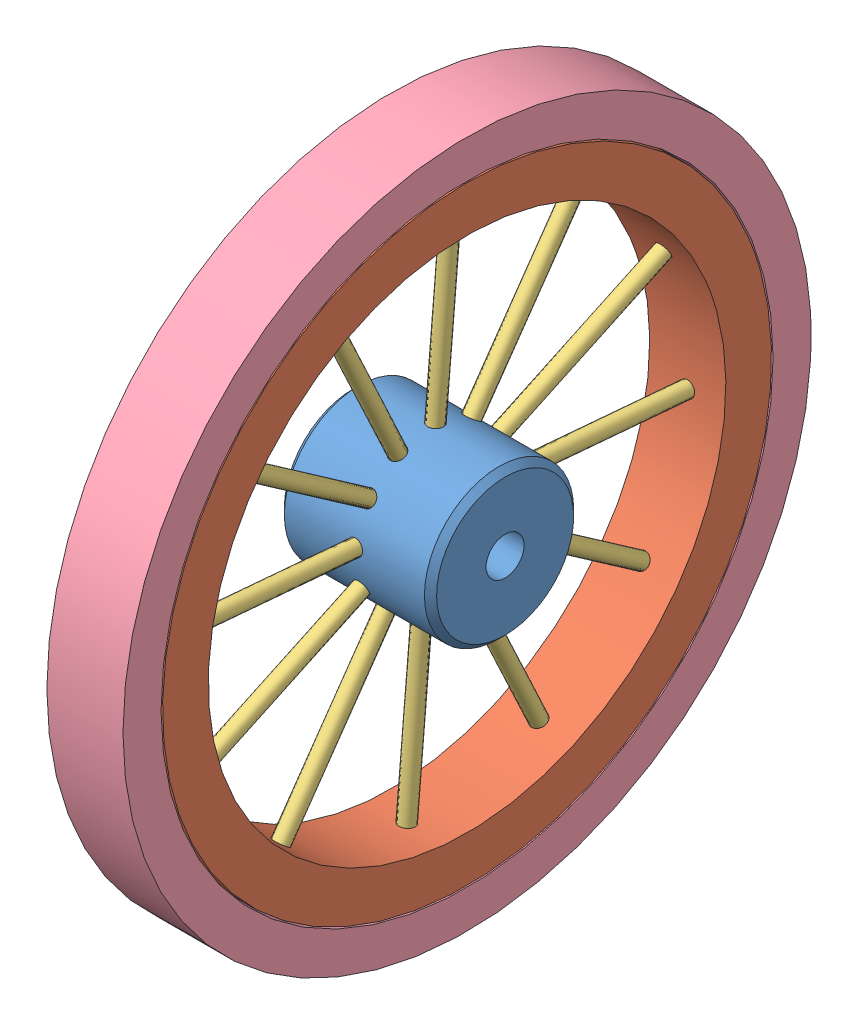
SolidWorks assembly Wheel, configuration Default. Lengths in mm.
Overall size (25.4 129.14 129.14).
15 component instances, 4 part files, 30 mates.
Components (placement in the parent):
- Hub-1: Hub [Default] at (11.6263 10.9898 19.9037) size (25.4 24.89 24.89)
- InnerRim-1: InnerRim [Default] at (11.6263 10.9898 19.9037) x (1 0 0) z (0 -0.325508 0.945539) size (12.7 101.6 101.6)
- Spoke-1: Spoke [Default] at (11.6263 -16.3912 7.1017) x (0.733186 -0.288022 0.616021) z (-0.680028 -0.310536 0.664175) size (2.54 40.64 2.54)
- Spoke-2: Spoke [Default] at (11.6263 -19.1238 22.5073) x (0.45302 0.076792 0.888187) z (-0.8915 0.039022 0.451337) size (2.54 40.64 2.54)
- Spoke-3: Spoke [Default] at (11.6263 -6.3218 -4.8737) x (-0.558086 -0.680204 0.47525) z (-0.829783 0.457484 -0.319638) size (2.54 40.64 2.54)
- Spoke-4: Spoke [Default] at (11.6263 -13.7876 37.2153) x (1 0 0) z (0 0.572739 0.819737) size (2.54 40.64 2.54)
- Spoke-5: Spoke [Default] at (11.6263 -1.8122 47.2847) x (0.999266 -0.0347 -0.016224) z (0.038306 0.905211 0.423233) size (2.54 40.64 2.54)
- Spoke-6: Spoke [Default] at (11.6263 8.3862 -10.21) x (0.430926 -0.899033 0.07773) z (-0.902387 -0.429324 0.037119) size (2.54 40.64 2.54)
- Spoke-7: Spoke [Default] at (11.6263 23.7918 -7.4773) x (1 0 0) z (0 0.905876 0.423544) size (2.54 40.64 2.54)
- Spoke-8: Spoke [Default] at (11.6263 13.5934 50.0173) x (0.808821 -0.58587 0.050654) z (-0.588055 -0.805815 0.06967) size (2.54 40.64 2.54)
- Spoke-9: Spoke [Default] at (11.6263 28.3014 44.6811) x (0.274974 0.788138 -0.550661) z (0.961452 -0.225406 0.157488) size (2.54 40.64 2.54)
- Spoke-10: Spoke [Default] at (11.6263 41.1035 17.3001) x (0.021573 0.086118 0.996051) z (-0.999767 0.001858 0.021493) size (2.54 40.64 2.54)
- Spoke-11: Spoke [Default] at (11.6263 35.7672 2.5921) x (0.597522 0.459253 0.657309) z (-0.801853 0.342224 0.489811) size (2.54 40.64 2.54)
- Spoke-12: Spoke [Default] at (11.6263 38.3708 32.7057) x (0.995605 -0.039667 0.08484) z (-0.093656 -0.421682 0.901894) size (2.54 40.64 2.54)
- OuterRim-1: OuterRim [Default] at (11.6263 10.9898 19.9037) size (12.7 114.81 114.81)
Mates (geometry in assembly coordinates):
- Coincident4: coincident aligned: plane of Hub-1 through (11.6263 10.9898 19.9037) normal (1 0 0); plane of InnerRim-1
- Concentric1: concentric aligned: cylinder of Hub-1 through (24.3263 10.9898 19.9037) axis (-1 0 0) radius 12.446; cylinder of InnerRim-1 through (17.9763 10.9898 19.9037) axis (-1 0 0) radius 43.18
- Concentric2: concentric anti-aligned: cylinder of Hub-1 through (11.6263 22.2643 25.1751) axis (0 0.905876 0.423544) radius 1.2891; cylinder of Spoke-12 through (11.6263 56.7782 41.3121) axis (0 -0.905876 -0.423544) radius 1.27
- Concentric3: concentric anti-aligned: cylinder of InnerRim-1 through (11.6263 57.0083 41.4197) axis (0 0.905876 0.423544) radius 1.2891; cylinder of Spoke-12 through (11.6263 56.7782 41.3121) axis (0 -0.905876 -0.423544) radius 1.27
- Coincident5: coincident anti-aligned: circle of Hub-1; plane of Spoke-12 through (11.6263 19.9634 24.0993) normal (0 -0.905876 -0.423544)
- Concentric4: concentric anti-aligned: cylinder of InnerRim-1 through (11.6263 61.601 15.5279) axis (0 0.996283 -0.086138) radius 1.2891; cylinder of Spoke-10 through (11.6263 61.3479 15.5497) axis (0 -0.996283 0.086138) radius 1.27
- Concentric5: concentric anti-aligned: cylinder of Hub-1 through (11.6263 23.3895 18.8316) axis (0 0.996283 -0.086138) radius 1.2891; cylinder of Spoke-10 through (11.6263 61.3479 15.5497) axis (0 -0.996283 0.086138) radius 1.27
- Concentric6: concentric anti-aligned: cylinder of InnerRim-1 through (11.6263 52.6325 -9.1915) axis (0 0.819737 -0.572739) radius 1.2891; cylinder of Spoke-11 through (11.6263 52.4243 -9.046) axis (0 -0.819737 0.572739) radius 1.27
- Concentric7: concentric anti-aligned: cylinder of InnerRim-1 through (11.6263 32.5058 -26.1148) axis (0 0.423544 -0.905876) radius 1.2891; cylinder of Spoke-7 through (11.6263 32.3982 -25.8847) axis (0 -0.423544 0.905876) radius 1.27
- Concentric8: concentric aligned: cylinder of InnerRim-1 through (11.6263 6.614 -30.7075) axis (0 -0.086138 -0.996283) radius 1.2891; cylinder of Spoke-6 through (11.6263 10.1365 10.0345) axis (0 -0.086138 -0.996283) radius 1.27
- Concentric9: concentric aligned: cylinder of InnerRim-1 through (11.6263 -18.1054 -21.739) axis (0 -0.572739 -0.819737) radius 1.2891; cylinder of Spoke-3 through (11.6263 5.3162 11.7834) axis (0 -0.572739 -0.819737) radius 1.27
- Concentric10: concentric aligned: cylinder of InnerRim-1 through (11.6263 -35.0287 -1.6123) axis (0 -0.905876 -0.423544) radius 1.2891; cylinder of Spoke-1 through (11.6263 2.0162 15.7081) axis (0 -0.905876 -0.423544) radius 1.27
- Concentric11: concentric aligned: cylinder of InnerRim-1 through (11.6263 -39.6214 24.2795) axis (0 -0.996283 0.086138) radius 1.2891; cylinder of Spoke-2 through (11.6263 1.1206 20.757) axis (0 -0.996283 0.086138) radius 1.27
- Concentric12: concentric aligned: cylinder of InnerRim-1 through (11.6263 -30.6529 48.9989) axis (0 -0.819737 0.572739) radius 1.2891; cylinder of Spoke-4 through (11.6263 2.8695 25.5772) axis (0 -0.819737 0.572739) radius 1.27
- Concentric13: concentric aligned: cylinder of InnerRim-1 through (11.6263 -10.5262 65.9222) axis (0 -0.423544 0.905876) radius 1.2891; cylinder of Spoke-5 through (11.6263 6.7942 28.8773) axis (0 -0.423544 0.905876) radius 1.27
- Concentric14: concentric anti-aligned: cylinder of InnerRim-1 through (11.6263 15.3656 70.5149) axis (0 0.086138 0.996283) radius 1.2891; cylinder of Spoke-8 through (11.6263 15.3437 70.2618) axis (0 -0.086138 -0.996283) radius 1.27
- Concentric15: concentric anti-aligned: cylinder of InnerRim-1 through (11.6263 40.085 61.5464) axis (0 0.572739 0.819737) radius 1.2891; cylinder of Spoke-9 through (11.6263 39.9395 61.3381) axis (0 -0.572739 -0.819737) radius 1.27
- Coincident6: coincident anti-aligned: circle of Hub-1; plane of Spoke-9 through (11.6263 16.6634 28.024) normal (0 -0.572739 -0.819737)
- Coincident7: coincident anti-aligned: circle of Hub-1; plane of Spoke-8 through (11.6263 11.8431 29.7729) normal (0 -0.086138 -0.996283)
- Coincident8: coincident anti-aligned: circle of Hub-1; plane of Spoke-5 through (11.6263 6.7942 28.8773) normal (0 0.423544 -0.905876)
- Coincident9: coincident anti-aligned: circle of Hub-1; plane of Spoke-4 through (11.6263 2.8695 25.5772) normal (0 0.819737 -0.572739)
- Coincident10: coincident anti-aligned: circle of Hub-1; plane of Spoke-2 through (11.6263 1.1206 20.757) normal (0 0.996283 -0.086138)
- Coincident11: coincident anti-aligned: circle of Hub-1; plane of Spoke-1 through (11.6263 2.0162 15.7081) normal (0 0.905876 0.423544)
- Coincident12: coincident anti-aligned: circle of Hub-1; plane of Spoke-3 through (11.6263 5.3162 11.7834) normal (0 0.572739 0.819737)
- Coincident13: coincident: circle of Hub-1; plane of Spoke-6 through (11.6263 10.1365 10.0345) normal (0 0.086138 0.996283)
- Coincident14: coincident: circle of Hub-1; plane of Spoke-7 through (11.6263 15.1854 10.9301) normal (0 -0.423544 0.905876)
- Coincident15: coincident anti-aligned: circle of Hub-1; plane of Spoke-11 through (11.6263 19.1101 14.2301) normal (0 -0.819737 0.572739)
- Coincident16: coincident anti-aligned: circle of Hub-1; plane of Spoke-10 through (11.6263 20.859 19.0504) normal (0 -0.996283 0.086138)
- Coincident18: coincident aligned: plane of InnerRim-1; plane of OuterRim-1 through (11.6263 10.9898 19.9037) normal (1 0 0)
- Concentric17: concentric aligned: circle of InnerRim-1; circle of OuterRim-1
